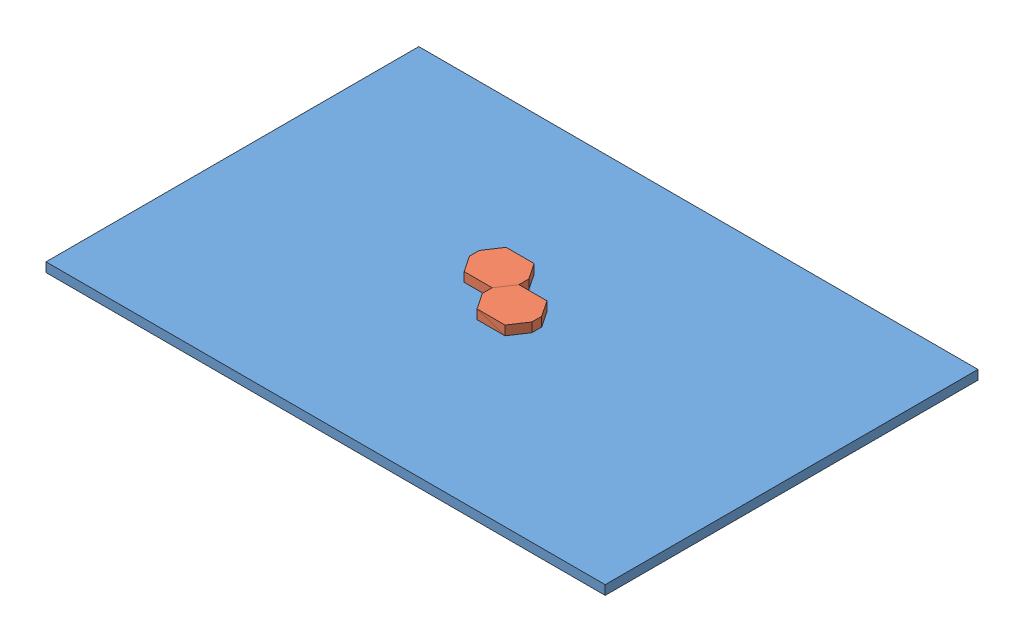
SolidWorks assembly two_node_3375, configuration Default. Lengths in mm.
Overall size (600 20 400).
3 component instances, 2 part files, 7 mates.
Components (placement in the parent):
- ground-1: ground [Default] at origin size (600 10 400)
- node_3375-1: node_3375 [Default] at origin size (53.08 10 45)
- node_3375-2: node_3375 [Default] at (-41.5735 0 -27.7785) size (53.08 10 45)
Mates (geometry in assembly coordinates):
- Coincident1: coincident aligned: plane of ground-1 through (0 0 0) normal (0 0 1)
- Coincident2: coincident aligned: plane of ground-1 through (0 0 0) normal (0 1 0)
- Coincident3: coincident aligned: plane of ground-1 through (0 0 0) normal (1 0 0)
- Coincident4: coincident aligned: plane of node_3375-1 through (0 0 0) normal (0 0 1)
- Coincident5: coincident aligned: plane of node_3375-1 through (0 0 0) normal (0 1 0)
- Coincident6: coincident aligned: plane of node_3375-1 through (0 0 0) normal (1 0 0)
- Coincident7: coincident: point of node_3375-1; unknown of node_3375-2
